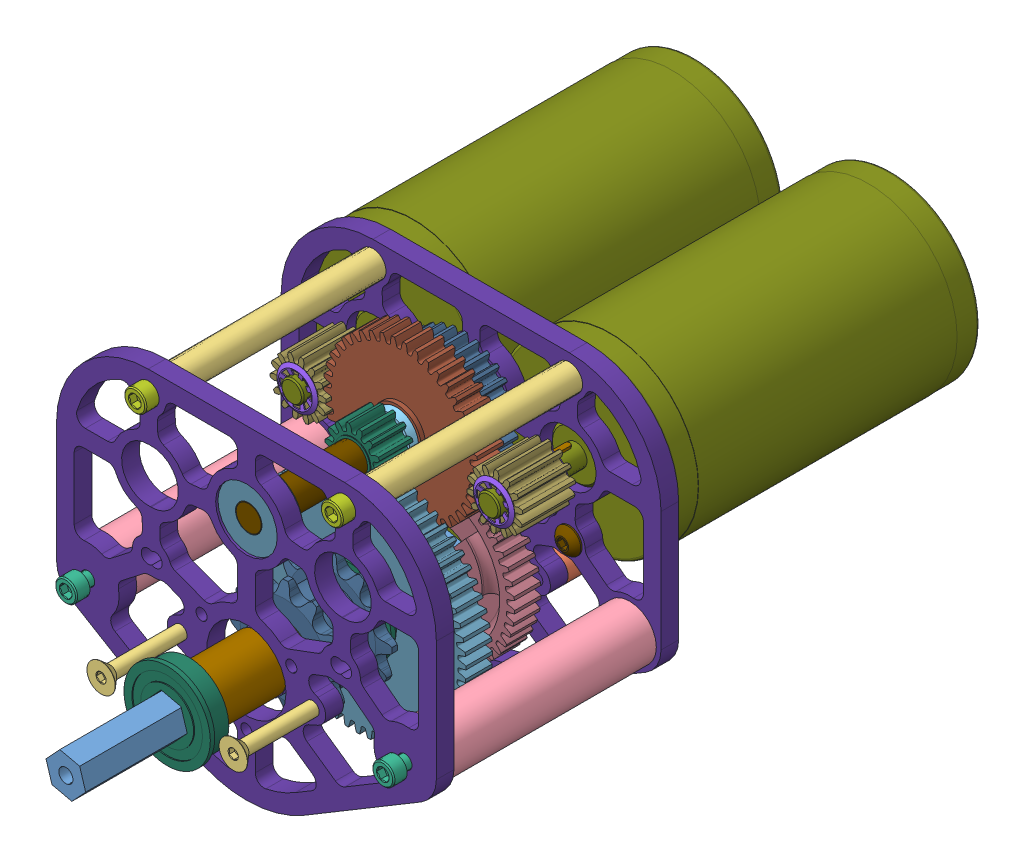
SolidWorks assembly WCP_DS_-_WCD_Base_Kit_217-3424, configuration Default. Lengths in mm.
Overall size (138.7 137.53 267).
71 component instances, 47 part files, 17 mates.
Components (placement in the parent):
- 217-3423-005 Rev1-1: 217-3423-005 Rev1 [Default] at (0 -47.0408 -46.0375) size (57.15 38.1 3.17)
- 217-3423-006 Rev1-1: 217-3423-006 Rev1 [Default] at (-23.8125 -47.0408 -23.8125) x (0 0 1) z (0.12883 0.991667 0) size (41.27 9.53 9.53)
- 217-3423-006 Rev1-2: 217-3423-006 Rev1 [Default] at (23.8125 -47.0408 -23.8125) x (0 0 1) z (-1 0 0) size (41.27 9.53 9.53)
- 217-3423-008 Rev1-1: 217-3423-008 Rev1 [Default] at (0 -47.0408 -11.7127) x (0 1 0) z (0 0 1) size (7.14 7.14 57.15)
- 217-3423-009 Rev3-1: 217-3423-009 Rev3 [Default] at (0 -47.0408 31.8928) x (-1 0 0) z (0 0 1) size (26.99 26.99 12.7)
- 217-2428-027 Rev1_97414A630-1: 217-2428-027 Rev1_97414A630 [Default] at (0 -47.0408 -19.3835) x (0 0 -1) z (-0.343927 0.938997 0) size (0.64 5.89 7.9)
- 217-3195-200 Rev1-1: 217-3195-200 Rev1 [Default] at (0 -47.0408 -23.0284) x (-0.655116 0.755528 0) z (0 0 -1) size (20.44 19.56 22.68)
  - 217-3195-010 Rev1-1: 217-3195-010 Rev1 [Default] x (-1 0 0) z (0 0 1) size (19.61 11.78 22.68)
  - 217-3195-010 Rev1-2: 217-3195-010 Rev1 [Default] at origin size (19.61 11.78 22.68)
  - 217-2778-NCQ8A075-050M_1032_Nut_90545A111-1: 217-2778-NCQ8A075-050M_1032_Nut_90545A111 [Default] at (0 0 2.5527) x (-0.5 0.866025 0) z (0 0 1) size (9.53 11 3.39)
  - 91251A107_91251A107-1: 91251A107_91251A107 [Default] at (-7.4168 -4.9375 -0.635) x (1 0 0) z (0 -1 0) size (4.65 4.65 10.79)
  - 91251A107_91251A107-2: 91251A107_91251A107 [Default] at (7.4168 4.9375 -0.635) x (-0.837169 0 -0.546944) z (0 1 0) size (4.65 4.65 10.79)
- 217-3489-1: 217-3489 [Default] at (0 -47.0408 -16.5831) x (0 0 -1) z (0.967286 -0.253689 0) size (4.77 12.7 12.7)
- 217-2778-001 Rev2_NCQ8A075-050M-1: 217-2778-001 Rev2_NCQ8A075-050M [Default] at (0 -47.0408 -61.087) x (-0.686336 0.727285 0) z (0 0 1) size (31.75 33.34 52.34)
  - 217-2778-NCQ8A075-050M_NCQ8 Tube_075A-1: 217-2778-NCQ8A075-050M_NCQ8 Tube_075A [Default] at origin size (31.75 33.34 26.92)
  - 217-2778-NCQ8A075-050M_NCQ8 Rod_075M-1: 217-2778-NCQ8A075-050M_NCQ8 Rod_075M [Default] at (0 0 3.6101) x (-1 0 0) z (0 0 1) size (18.95 18.95 35.27)
  - 217-2778-NCQ8A075-050M_Snap Ring_075-1: 217-2778-NCQ8A075-050M_Snap Ring_075 [Default] at (0 0 10.362) size (21 20.74 0.97)
- 217-2731-1: 217-2731 [Default] at (0 -47.0408 3.175) x (-0.539745 -0.841828 0) z (0.841828 -0.539745 0) size (31.12 7.94 31.12)
- 217-2733-1: 217-2733 [Default] at (0 0 4.7625) x (0 0 -1) z (0.79471 -0.606989 0) size (7.11 24.61 24.61)
- 217-2733-2: 217-2733 [Default] at (0 0 76.2) x (0 0 1) z (-0.575096 -0.818086 0) size (7.11 24.61 24.61)
- 217-2734-1: 217-2734 [Default] at (0 -47.0408 39.6557) x (0.92364 -0.383262 0) z (-0.383262 -0.92364 0) size (31.12 7.94 31.12)
- 217-2734-2: 217-2734 [Default] at (0 -47.0408 104.775) x (0.295645 -0.955298 0) z (-0.955298 -0.295645 0) size (31.12 7.94 31.12)
- 217-2743-1: 217-2743 [Default] at (0 -47.0408 7.9057) x (0 0 -1) z (0.947967 0.31837 0) size (7.94 28.57 28.57)
- 217-3421-007 Rev1-1: 217-3421-007 Rev1 [Default] at (-23.8125 -47.0408 -47.625) x (0 0 1) z (-0.899493 -0.436936 0) size (55.85 7.92 7.92)
- 217-3421-007 Rev1-2: 217-3421-007 Rev1 [Default] at (23.8125 -47.0408 -47.625) x (0 0 1) z (-0.899493 -0.436936 0) size (55.85 7.92 7.92)
- 217-3421-009 Rev1-1: 217-3421-009 Rev1 [Default] at (35.4115 -29.21 3.175) x (0 0 -1) z (0.930255 -0.366914 0) size (15.78 9.26 9.25)
- 217-3421-009 Rev1-2: 217-3421-009 Rev1 [Default] at (-35.4115 -29.21 3.175) x (0 0 -1) z (0.930255 -0.366914 0) size (15.78 9.26 9.25)
- 217-3421-010 Rev1-1: 217-3421-010 Rev1 [Default] at (57.15 -47.0408 -3.175) x (-0.764138 0.645053 0) z (-0.645053 -0.764138 0) size (9.53 6.13 11)
- 217-3421-010 Rev1-2: 217-3421-010 Rev1 [Default] at (-57.15 -47.0408 -3.175) x (-0.764138 0.645053 0) z (-0.645053 -0.764138 0) size (9.53 6.13 11)
- 217-3421-011 Rev2_97633A200-1: 217-3421-011 Rev2_97633A200 [Default] at (0 -47.0408 -5.2388) x (0 0 -1) z (0.999706 0.024248 0) size (0.89 16.1 14.34)
- 217-3422-007 Rev1-1: 217-3422-007 Rev1 [Default] at (23.8125 -47.0408 109.4868) x (0 0 1) z (-0.857808 -0.51397 0) size (35.11 10.21 10.21)
- 217-3422-007 Rev1-2: 217-3422-007 Rev1 [Default] at (-23.8125 -47.0408 109.4868) x (0 0 1) z (-0.979216 -0.202822 0) size (35.11 10.21 10.21)
- 217-3423-014 Rev1-1: 217-3423-014 Rev1 [Default] at (-13.4938 -47.0408 31.8928) x (0 -0.990182 -0.139784) z (-1 0 0) size (4.65 4.65 26.79)
- 217-3423-016 Rev1-1: 217-3423-016 Rev1 [Default] at (16.1541 -37.7142 -4.7625) x (0 0 1) z (-0.99993 -0.011852 0) size (11.03 9.26 9.25)
- 217-3423-016 Rev1-2: 217-3423-016 Rev1 [Default] at (-16.1541 -37.7142 -4.7625) x (0 0 1) z (-0.99993 -0.011852 0) size (11.03 9.26 9.25)
- 217-3423-016 Rev1-3: 217-3423-016 Rev1 [Default] at (0 -65.6939 -4.7625) x (0 0 1) z (0.05928 -0.998241 0) size (11.03 9.26 9.25)
- 217-3424-003 Rev1-1: 217-3424-003 Rev1 [Default] at (57.15 -47.0408 87.3125) x (0 0 -1) z (-0.820506 -0.571638 0) size (100.3 7.92 7.92)
- 217-3424-003 Rev1-2: 217-3424-003 Rev1 [Default] at (-57.15 -47.0408 87.3125) x (0 0 -1) z (0.916469 0.400106 0) size (100.3 7.92 7.92)
- 217-3424-004 Rev1-1: 217-3424-004 Rev1 [Default] at (35.4115 21.59 84.1375) x (0 0 -1) z (0.97248 0.232987 0) size (98.72 7.92 7.92)
- 217-3424-004 Rev1-2: 217-3424-004 Rev1 [Default] at (-35.4115 21.59 84.1375) x (0 0 -1) z (0.941602 0.336727 0) size (98.72 7.92 7.92)
- 217-2614-002_98430A132-1: 217-2614-002_98430A132 [Default] at (35.4115 -3.81 9.9695) x (0 0 1) z (-0.864814 -0.502092 0) size (1.2 14.83 14.83)
- 217-2614-002_98430A132-2: 217-2614-002_98430A132 [Default] at (35.4115 -3.81 31.1531) x (0 0 -1) z (-0.416152 -0.909295 0) size (1.2 14.83 14.83)
- 217-2614-002_98430A132-3: 217-2614-002_98430A132 [Default] at (-35.4115 -3.81 31.1531) x (0 0 -1) z (-0.945551 0.325474 0) size (1.2 14.83 14.83)
- 217-2614-002_98430A132-4: 217-2614-002_98430A132 [Default] at (-35.4115 -3.81 9.9695) x (0 0 1) z (-0.989494 0.144574 0) size (1.2 14.83 14.83)
- 217-2761-001 rev1-1: 217-2761-001 rev1 [Default] at (-35.4115 -0.01 12.925) size (2 2 20)
- 217-2761-001 rev1-2: 217-2761-001 rev1 [Default] at (35.4115 -0.01 12.925) size (2 2 20)
- 217-3210-001 Rev1_30t-1: 217-3210-001 Rev1_30t [Default] at (0 0 11.0871) x (0.988842 0.148971 0) z (0 0 1) size (41.01 41.12 12.65)
- 217-3215-001 Rev1_42t-1: 217-3215-001 Rev1_42t [Default] at (0 0 23.7363) x (0.940655 -0.339365 0) z (0 0 1) size (56.22 56.3 12.65)
- 217-3414-001 Rev1_14t Steel Pinion-1: 217-3414-001 Rev1_14t Steel Pinion [Default] at (-35.4115 -3.81 20.5613) x (0.095909 -0.99539 0) z (0 0 1) size (20.32 20.6 19.05)
- 217-3414-001 Rev1_14t Steel Pinion-2: 217-3414-001 Rev1_14t Steel Pinion [Default] at (35.4115 -3.81 20.5613) x (-0.277698 -0.960668 0) z (0 0 1) size (20.32 20.6 19.05)
- 217-3418-001 Rev2_44t-1: 217-3418-001 Rev2_44t [Default] at (0 -47.0408 11.922) x (0.629196 0.777247 0) z (0 0 1) size (58.67 58.67 9.53)
- 217-3420-001 Rev2_60t-1: 217-3420-001 Rev2_60t [Default] at (0 -47.0408 39.6082) x (0.535414 0.84459 0) z (0 0 -1) size (78.95 78.95 9.53)
- 217-3100-001_14t-1: 217-3100-001_14t [Default] at (0 0 39.5859) x (0.763916 -0.645315 0) z (0 0 1) size (20.32 20.6 12.7)
- 217-2000-1: 217-2000 [Default] at (35.4115 -3.81 -3.175) x (0 0 -1) z (1 0 0) size (150.2 64.01 64.01)
- 217-2000-2: 217-2000 [Default] at (-35.4115 -3.81 -3.175) x (0 0 -1) z (1 0 0) size (150.2 64.01 64.01)
- 217-3423-001 Rev1_Default_As Machined_-1: 217-3423-001 Rev1_Default_As Machined_ [Default] at origin size (136.86 116.89 6.35)
- 217-3423-001 Rev1_Default_As Machined_-2: 217-3423-001 Rev1_Default_As Machined_ [Default] at (0 0 80.9625) x (-1 0 0) z (0 0 -1) size (136.86 116.89 6.35)
- 217-3424-005 Rev1-1: 217-3424-005 Rev1 [Default] at (0 0 40.4813) size (11.11 11.11 85.72)
- 217-3423-003 Rev1-1: 217-3423-003 Rev1 [Default] at (0.0082 -47.3778 25.8921) x (-0.67949 -0.733685 0) z (0 0 1) size (18.33 15.88 156.5)
- 217-3423-004 Rev1-1: 217-3423-004 Rev1 [Default] at (0 -47.0408 3.556) size (19.05 19.05 0.76)
- 217-3424-001 Rev1-1: 217-3424-001 Rev1 [Default] at (35.4115 21.59 40.4813) x (-0.974142 0.225938 0) z (0 0 1) size (9.53 9.53 74.61)
- 217-3424-001 Rev1-2: 217-3424-001 Rev1 [Default] at (-35.4115 21.59 40.4813) size (9.53 9.53 74.61)
- 217-3424-002 Rev1-1: 217-3424-002 Rev1 [Default] at (-57.15 -47.0408 40.4813) size (19.13 19.13 80.96)
- 217-3424-002 Rev1-2: 217-3424-002 Rev1 [Default] at (57.15 -47.0408 40.4813) x (0.857249 -0.514902 0) z (0 0 1) size (19.13 19.13 80.96)
- 217-3256-001 Rev1-1: 217-3256-001 Rev1 [Default] at (0 0 31.6484) x (0.920904 0.389789 0) z (0 0 1) size (15.88 15.88 3.17)
- 217-3257-001 Rev1-1: 217-3257-001 Rev1 [Default] at (0.0082 -47.3778 48.387) x (-0.295645 0.955298 0) z (0 0 1) size (19.5 19.5 1.59)
- 217-2758-001 Rev1-1: 217-2758-001 Rev1 [Default] at (0.0082 -47.3778 72.117) x (-0.221613 -0.975135 0) z (0 0 1) size (19.05 19.05 3.17)
- 217-3259-001 Rev1-1: 217-3259-001 Rev1 [Default] at (0.0082 -47.3778 76.2) x (-0.295645 0.955298 0) z (0 0 1) size (19.5 19.5 6.35)
- 217-3263-001 Rev1-1: 217-3263-001 Rev1 [Default] at (0 -47.0408 92.075) size (19.5 19.5 25.4)
- 217-3422-004 Rev2-1: 217-3422-004 Rev2 [Default] at (0 -47.0408 111.125) size (72.39 47.62 34.67) (hidden)
- 10-441 #35 double sprocket-1: 10-441 #35 double sprocket [Default] at (0.0082 -47.3778 51.3271) x (0.221613 0.975135 0) z (0 0 1) size (40.29 40.29 21.35)
Mates (geometry in assembly coordinates):
- Coincident1: coincident anti-aligned: plane of 217-3421-011 Rev2_97633A200-1 through (0 -47.0408 -5.6833) normal (0 0 -1); plane of 217-3423-003 Rev1-1 through (0.0082 -47.3778 -5.6833) normal (0 0 1)
- Concentric1: concentric aligned: circle of 217-3421-011 Rev2_97633A200-1; circle of 217-3423-003 Rev1-1
- Concentric3: concentric anti-aligned: cylinder of 217-2734-2 through (0 -47.0408 104.775) axis (0 0 1) radius 14.2748; cylinder of 217-3422-004 Rev2-1 through (0 -47.0408 112.7125) axis (0 0 -1) radius 14.2748
- Concentric6: concentric anti-aligned: circle of 10-441 #35 double sprocket-1; cylinder of 217-3423-003 Rev1-1 through (0.0082 -47.3778 187.4203) axis (0 0 1) radius 2.5527
- Parallel4: parallel anti-aligned: plane of 217-3423-003 Rev1-1 through (-7.1419 -45.7528 187.4203) normal (-0.955298 -0.295645 0); plane of 10-441 #35 double sprocket-1 through (-7.1562 -45.7496 49.1797) normal (0.955298 0.295645 0)
- Concentric8: concentric anti-aligned: circle of 217-3259-001 Rev1-1; cylinder of 217-3423-003 Rev1-1 through (0.0082 -47.3778 187.4203) axis (0 0 1) radius 2.5527
- Parallel5: parallel anti-aligned: plane of 217-3423-003 Rev1-1 through (-4.9741 -52.7574 187.4203) normal (-0.221613 -0.975135 0); plane of 217-3259-001 Rev1-1 through (-5.0737 -52.865 79.375) normal (0.221613 0.975135 0)
- Coincident11: coincident anti-aligned: plane of 217-3259-001 Rev1-1 through (0.0082 -47.3778 79.375) normal (0 0 1); plane of 217-3263-001 Rev1-1 through (0 -47.0408 79.375) normal (0 0 -1)
- Concentric10: concentric anti-aligned: circle of 217-3257-001 Rev1-1; cylinder of 217-3423-003 Rev1-1 through (0.0082 -47.3778 187.4203) axis (0 0 1) radius 2.5527
- Parallel7: parallel anti-aligned: plane of 217-3423-003 Rev1-1 through (2.1759 -54.3823 187.4203) normal (0.733685 -0.67949 0); plane of 217-3257-001 Rev1-1 through (2.2193 -54.5224 49.1808) normal (-0.733685 0.67949 0)
- Coincident15: coincident anti-aligned: circle of 217-2734-1; plane of 217-3257-001 Rev1-1 through (0.0082 -47.3778 47.5932) normal (0 0 -1)
- Coincident16: coincident anti-aligned: plane of 217-3257-001 Rev1-1 through (0.0082 -47.3778 49.1808) normal (0 0 1); plane of 10-441 #35 double sprocket-1 through (-15.4661 -43.861 49.1808) normal (0 0 -1)
- Coincident18: coincident anti-aligned: plane of 217-2734-2 through (4.5995 -61.9028 111.125) normal (0 0 -1); plane of 217-3422-004 Rev2-1 through (0 -47.0408 111.125) normal (0 0 1)
- Parallel10: parallel anti-aligned: plane of 217-2734-2 through (-4.9901 -52.4289 104.775) normal (0.221613 0.975135 0); plane of 217-3423-003 Rev1-1 through (-4.9741 -52.7574 187.4203) normal (-0.221613 -0.975135 0)
- Concentric11: concentric aligned: circle of 217-2758-001 Rev1-1; cylinder of 217-3423-003 Rev1-1 through (0.0082 -47.3778 187.4203) axis (0 0 1) radius 2.5527
- Parallel11: parallel anti-aligned: plane of 217-3423-003 Rev1-1 through (4.9904 -41.9981 187.4203) normal (0.221613 0.975135 0); plane of 217-2758-001 Rev1-1 through (5.0901 -41.8905 73.7045) normal (-0.221613 -0.975135 0)
- Coincident22: coincident anti-aligned: plane of 217-2758-001 Rev1-1 through (0.0082 -47.3778 70.5294) normal (0 0 -1); plane of 10-441 #35 double sprocket-1 through (-15.4661 -43.861 70.5294) normal (0 0 1)
